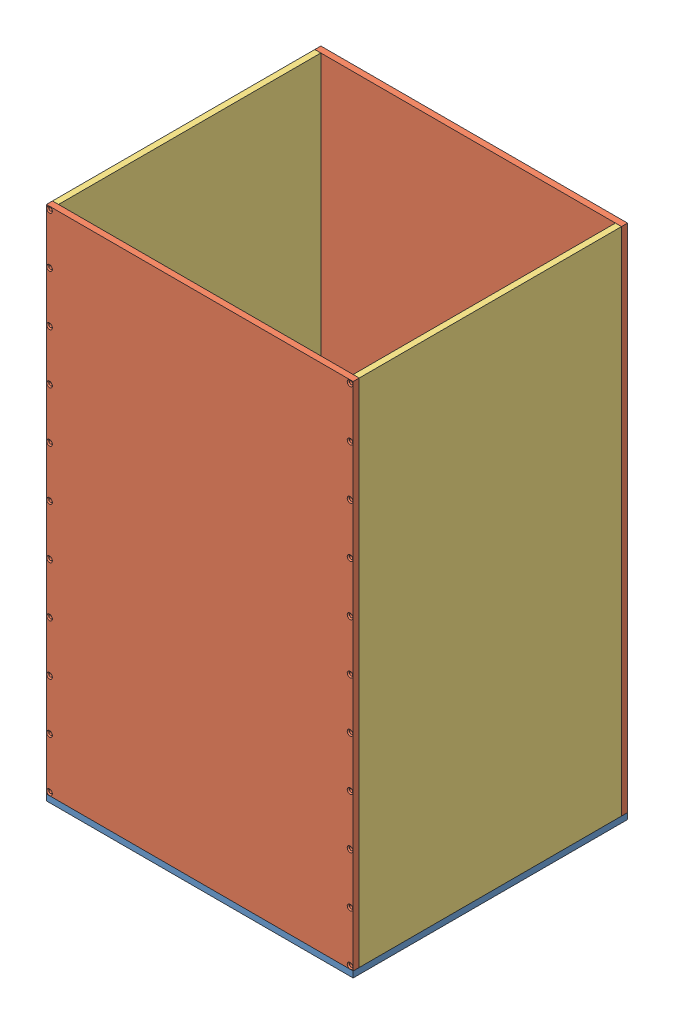
SolidWorks assembly Enclosure, configuration Default. Lengths in mm.
Overall size (304 512 272).
5 component instances, 3 part files, 12 mates.
Components (placement in the parent):
- Bottom_tray-1: Bottom_tray [Default] at origin size (304 6 272)
- Front-Back-1: Front-Back [Default] at (0 6 -6) size (304 506 6)
- Front-Back-2: Front-Back [Default] at (304 6 -266) x (-1 0 0) z (0 0 -1) size (304 506 6)
- side-side-1: side-side [Default] at (304 6 -266) x (0 0 1) z (-1 0 0) size (260 506 6)
- side-side-2: side-side [Default] at (0 6 -6) x (0 0 -1) z (1 0 0) size (260 506 6)
Mates (geometry in assembly coordinates):
- Coincident2: coincident: plane of assembly; plane of assembly; plane of Bottom_tray-1 through (0 6 0) normal (0 1 0); plane of Front-Back-1 through (0 6 0) normal (0 -1 0)
- Coincident4: coincident: plane of assembly; plane of assembly; plane of Bottom_tray-1 through (0 6 0) normal (-1 0 0); plane of Front-Back-1 through (0 6 0) normal (-1 0 0)
- Coincident5: coincident: plane of Bottom_tray-1 through (0 6 0) normal (0 1 0); plane of ? through (304 6 -296.034) normal (0 -1 0)
- Coincident7: coincident: plane of Bottom_tray-1 through (304 6 0) normal (1 0 0); plane of ? through (304 6 -296.034) normal (1 0 0)
- Coincident8: coincident: plane of Bottom_tray-1 through (0 6 0) normal (0 1 0); plane of ? through (156.193 1.1823 -253.1696) normal (0 -1 0)
- Coincident10: coincident: plane of Bottom_tray-1 through (304 6 0) normal (1 0 0); plane of ? through (162.193 1.1823 -253.1696) normal (1 0 0)
- Coincident12: coincident: plane of Bottom_tray-1 through (0 6 0) normal (0 1 0); plane of ? through (6 6 -29.2433) normal (0 -1 0)
- Coincident13: coincident: plane of Bottom_tray-1 through (0 6 0) normal (-1 0 0); plane of ? through (0 6 -29.2433) normal (-1 0 0)
- Coincident15: coincident: plane of assembly; plane of assembly; plane of Bottom_tray-1 through (0 6 0) normal (0 0 1); plane of Front-Back-1 through (0 6 0) normal (0 0 1)
- Coincident16: coincident: plane of assembly; plane of assembly; plane of Bottom_tray-1 through (0 6 -272) normal (0 0 -1); plane of Front-Back-2 through (304 6 -272) normal (0 0 -1)
- Coincident17: coincident: plane of assembly; line of assembly; plane of Front-Back-1 through (0 6 -6) normal (0 0 -1); line of side-side-2 through (0 512 -6) axis (0 -1 0)
- Coincident18: coincident: plane of assembly; plane of assembly; plane of Front-Back-1 through (0 6 -6) normal (0 0 -1); plane of side-side-1 through (298 6 -6) normal (0 0 1)
